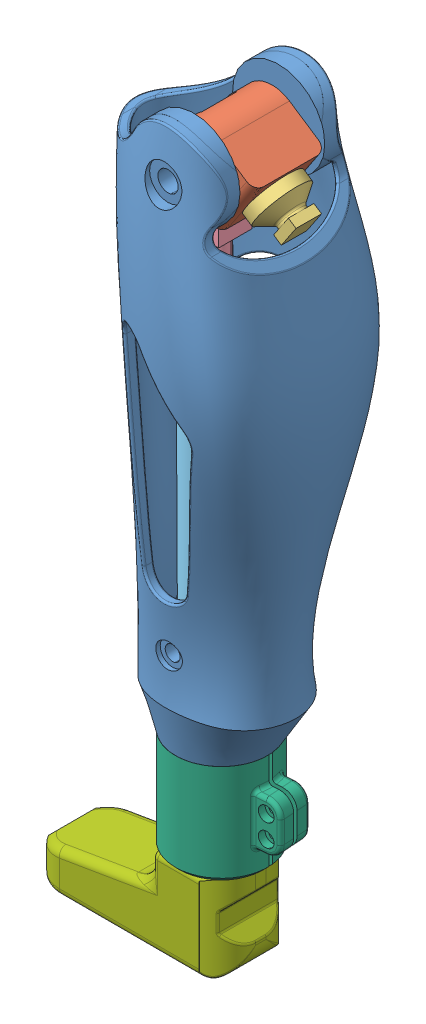
SolidWorks assembly anirudh, configuration Default. Lengths in mm.
Overall size (155.04 495.64 328.88).
7 component instances, 7 part files, 14 mates.
Components (placement in the parent):
- fig 10 lower app-1: fig 10 lower app [Default] at (63.9958 51.0011 274.4664) size (117.32 325.99 107.23)
- FIG 4 APP JOINT-1: FIG 4 APP JOINT [Default] at (71.9958 306.0011 254.9664) x (-0.553016 -0.833171 0) z (0 0 1) size (50.25 41 39)
- Copy of Part1^anirudh-1: Copy of Part1^anirudh [Default] at (81.2096 276.4841 274.7868) x (0.009086 0.013688 0.999865) z (0.833171 -0.553016 0) size (29 29 18.5) (virtual)
- FIG 5 PNU PISTON SHAFT-1: FIG 5 PNU PISTON SHAFT [Default] at (63.6477 140.3406 274.4664) x (0 0 -1) z (-0.005328 0.999986 0) size (18 17 150.5)
- FI 6 PNU CYLINDER-1: FI 6 PNU CYLINDER [Default] at (63.9372 86.001 274.4664) x (0 0 1) z (-0.999986 -0.005328 0) size (40 167 35)
- FIG 2 CONNECTOR-1: FIG 2 CONNECTOR [Default] at (63.9958 -28.9989 274.4664) x (0.071938 0 0.997409) z (-0.997409 0 0.071938) size (50 55 62.5)
- shoe-2: shoe [Default] at (56.9661 -64.4098 268.1352) size (106.42 66.03 41.42)
Mates (geometry in assembly coordinates):
- Concentric1: concentric aligned: cylinder of fig 10 lower app-1 through (71.9958 306.0011 219.4664) axis (0 0 1) radius 5.5; cylinder of FIG 4 APP JOINT-1 through (71.9958 306.0011 291.9664) axis (0 0 1) radius 3.4
- Width1: width anti-aligned: plane of fig 10 lower app-1 through (71.9958 306.0011 297.4664) normal (0 0 -1); plane of fig 10 lower app-1 through (71.9958 306.0011 251.4664) normal (0 0 1); plane of FIG 4 APP JOINT-1 through (57.693 293.4939 293.9664) normal (0 0 1); plane of FIG 4 APP JOINT-1 through (57.693 293.4939 254.9664) normal (0 0 -1)
- Concentric2: concentric aligned: cylinder of FIG 4 APP JOINT-1 through (91.9928 292.7282 274.4664) axis (-0.833171 0.553016 0) radius 2.25; cylinder of Copy of Part1^anirudh-1 through (91.9919 292.7287 274.4664) axis (-0.833171 0.553016 0) radius 2.25
- Coincident1: coincident anti-aligned: plane of FIG 4 APP JOINT-1 through (101.3932 306.8926 293.9664) normal (0.833171 -0.553016 0); plane of Copy of Part1^anirudh-1 through (91.9919 292.7287 274.4664) normal (-0.833171 0.553016 0)
- Concentric3: concentric anti-aligned: cylinder of FIG 4 APP JOINT-1 through (62.8911 282.3386 288.9664) axis (0 0 1) radius 2.1; cylinder of FIG 5 PNU PISTON SHAFT-1 through (62.8911 282.3386 283.4674) axis (0 0 -1) radius 2.75
- Width2: width anti-aligned: plane of FIG 4 APP JOINT-1 through (117.1003 343.2147 264.9664) normal (0 0 1); plane of FIG 4 APP JOINT-1 through (117.1003 343.2147 283.9664) normal (0 0 -1); plane of FIG 5 PNU PISTON SHAFT-1 through (54.346 290.7932 265.4664) normal (0 0 -1); plane of FIG 5 PNU PISTON SHAFT-1 through (54.346 290.7932 283.4664) normal (0 0 1)
- Concentric4: concentric anti-aligned: cylinder of fig 10 lower app-1 through (63.9958 75.0011 244.7164) axis (0 0 1) radius 4.05; cylinder of FI 6 PNU CYLINDER-1 through (63.9958 75.0011 259.4664) axis (0 0 -1) radius 4
- Width3: width anti-aligned: plane of fig 10 lower app-1 through (63.9958 75.0011 253.9664) normal (0 0 1); plane of fig 10 lower app-1 through (63.9958 75.0011 294.9664) normal (0 0 -1); plane of FI 6 PNU CYLINDER-1 through (59.0279 68.9746 254.4664) normal (0 0 -1); plane of FI 6 PNU CYLINDER-1 through (59.0279 68.9746 294.4664) normal (0 0 1)
- Concentric5: concentric anti-aligned: cylinder of FIG 5 PNU PISTON SHAFT-1 through (63.0084 260.3389 274.4664) axis (0.005328 -0.999986 0) radius 5; cylinder of FI 6 PNU CYLINDER-1 through (63.9372 86.001 274.4664) axis (-0.005328 0.999986 0) radius 5
- Concentric6: concentric aligned: cylinder of fig 10 lower app-1 through (63.9958 26.0011 274.4664) axis (0 -1 0) radius 17.5; cylinder of FIG 2 CONNECTOR-1 through (63.9958 26.0011 274.4664) axis (0 -1 0) radius 20
- Coincident2: coincident anti-aligned: plane of fig 10 lower app-1 through (63.9958 26.0011 274.4664) normal (0 -1 0); plane of FIG 2 CONNECTOR-1 through (63.9958 26.0011 274.4664) normal (0 1 0)
- Coincident3: coincident anti-aligned: plane of FIG 2 CONNECTOR-1 through (63.9958 -28.9989 274.4664) normal (0 -1 0); plane of shoe-2 through (46.5042 -28.9989 294.4664) normal (0 1 0)
- Parallel1: parallel anti-aligned: plane of fig 10 lower app-1 through (58.4058 19.3911 279.6664) normal (0 0 -1); plane of shoe-2 through (66.102 -20.5989 280.4664) normal (0 0 1)
- Coincident5: coincident anti-aligned: plane of fig 10 lower app-1 through (58.4058 19.3911 269.2664) normal (0 0 1); plane of shoe-2 through (66.102 -20.5989 269.2664) normal (0 0 -1)
